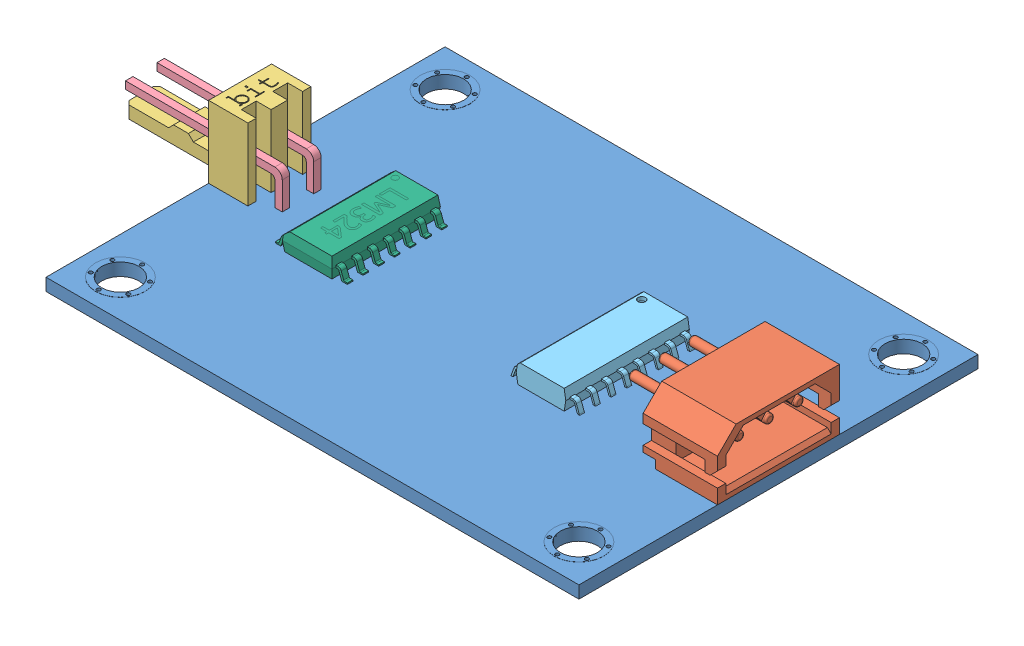
SolidWorks assembly CQRobot Ocean, configuration Default. Lengths in mm.
Overall size (51 9.91 32.2).
9 component instances, 6 part files, 12 mates.
Components (placement in the parent):
- qcbase-1: qcbase [Default] at (-59.9132 10.1047 24.4107) size (43 1.02 32.2)
- Mini-SPOX 2.50mm 3pin-1: Mini-SPOX 2.50mm 3pin [Default] at (-42.4132 16.0047 19.4907) x (0 0 1) z (1 0 0) size (9.84 4.9 9.5)
- Molex-2.54-2pin-angle-1: Molex-2.54-2pin-angle [Default] at (-84.6052 2.8347 23.8296) x (0 0 -1) z (0 1 0) size (5.08 12.97 9.91)
  - Molex-2.54-2pin-angle.STEP-1: Molex-2.54-2pin-angle.STEP [Default] at origin size (5.08 12.97 9.91)
    - Pieza2.STEP-1: Pieza2.STEP [Default] at (-1.0211 -6.362 11.17) size (5.08 11.17 5.8)
    - pin_90.STEP-1: pin_90.STEP [Default] at (-2.5911 -7.5649 10.51) x (0 0 1) z (0 1 0) size (6.95 0.6 12.85)
    - pin_90.STEP-2: pin_90.STEP [Default] at (-0.0511 -7.5649 10.51) x (0 0 1) z (0 1 0) size (6.95 0.6 12.85)
- User Library-so16-1-1: User Library-so16-1 [Default] at (-53.0154 11.8297 23.984) x (0 0 1) z (-1 0 0) size (9.97 1.76 6.14)
- LM324S014-1: LM324S014 [Default] at (-71.6513 11.1047 24.8289) x (0 0 1) z (0 1 0) size (8.75 5.8 1.7)
Mates (geometry in assembly coordinates):
- Coincident1: coincident anti-aligned: plane of qcbase-1 through (-59.9132 11.1047 24.4107) normal (0 1 0); plane of Mini-SPOX 2.50mm 3pin-1 through (-42.4132 11.1047 29.3307) normal (0 -1 0)
- Coincident2: coincident aligned: plane of qcbase-1 through (-38.4132 11.1047 8.3107) normal (1 0 0); plane of Mini-SPOX 2.50mm 3pin-1 through (-38.4132 14.8897 24.4107) normal (1 0 0)
- Distance1: distance = 11.18 mm aligned: plane of Mini-SPOX 2.50mm 3pin-1 through (-42.4132 14.5047 29.3307) normal (0 0 1); plane of qcbase-1 through (-81.4132 11.1047 40.5107) normal (0 0 1)
- Coincident4: coincident anti-aligned: plane of qcbase-1 through (-59.9132 11.1047 24.4107) normal (0 1 0); plane of Molex-2.54-2pin-angle-1/Molex-2.54-2pin-angle.STEP-1/Pieza2.STEP-1 through (-81.4132 11.1047 22.3107) normal (0 -1 0)
- Coincident5: coincident aligned: plane of qcbase-1 through (-81.4132 11.1047 8.3107) normal (-1 0 0); plane of Molex-2.54-2pin-angle-1/Molex-2.54-2pin-angle.STEP-1/Pieza2.STEP-1 through (-81.4132 14.0047 24.8507) normal (-1 0 0)
- Distance2: distance = 14 mm aligned: plane of Molex-2.54-2pin-angle-1/Molex-2.54-2pin-angle.STEP-1/Pieza2.STEP-1 through (-81.4132 11.1047 22.3107) normal (0 0 -1); plane of qcbase-1 through (-81.4132 11.1047 8.3107) normal (0 0 -1)
- Coincident7: coincident anti-aligned: plane of qcbase-1 through (-59.9132 11.1047 24.4107) normal (0 1 0); plane of User Library-so16-1-1 through (-54.8831 11.1047 14.3509) normal (0 -1 0)
- Parallel1: parallel aligned: plane of qcbase-1 through (-81.4132 11.1047 8.3107) normal (0 0 -1); plane of User Library-so16-1-1 through (-55.2504 11.9797 18.999) normal (0 0 -1)
- Lock1: lock: unknown of qcbase-1; unknown of User Library-so16-1-1
- Coincident19: coincident anti-aligned: plane of qcbase-1 through (-59.9132 11.1047 24.4107) normal (0 1 0); plane of LM324S014-1 through (-71.6513 11.1047 24.8289) normal (0 -1 0)
- Parallel12: parallel aligned: plane of qcbase-1 through (-81.4132 11.1047 8.3107) normal (0 0 -1); plane of LM324S014-1 through (-69.2475 11.5126 20.7939) normal (0 0 -1)
- Lock2: lock: unknown of qcbase-1; unknown of LM324S014-1
